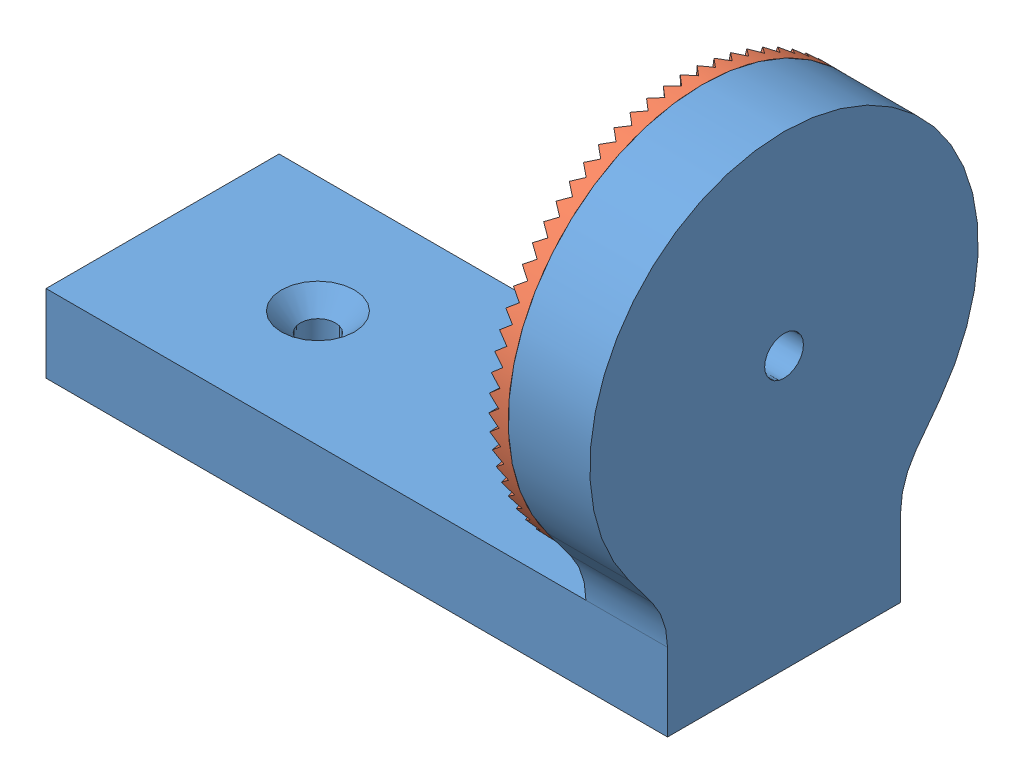
SolidWorks assembly arm-mount2, configuration Default. Lengths in mm.
Overall size (82.31 63.31 60.43).
2 component instances, 2 part files, 2 mates.
Components (placement in the parent):
- armmount2-1: armmount2 [Default] at origin size (80 60 50)
- bevel4-1: bevel4 [Default] at (32 35 -25) x (0 0.115985 0.993251) z (0 -0.993251 0.115985) size (55 28.07 50)
Mates (geometry in assembly coordinates):
- Coincident1: coincident anti-aligned: plane of armmount2-1 through (29.5 60 -50) normal (-1 0 0); plane of bevel4-1 through (29.5 35 -25) normal (1 0 0)
- Concentric1: concentric anti-aligned: circle of armmount2-1; circle of bevel4-1
